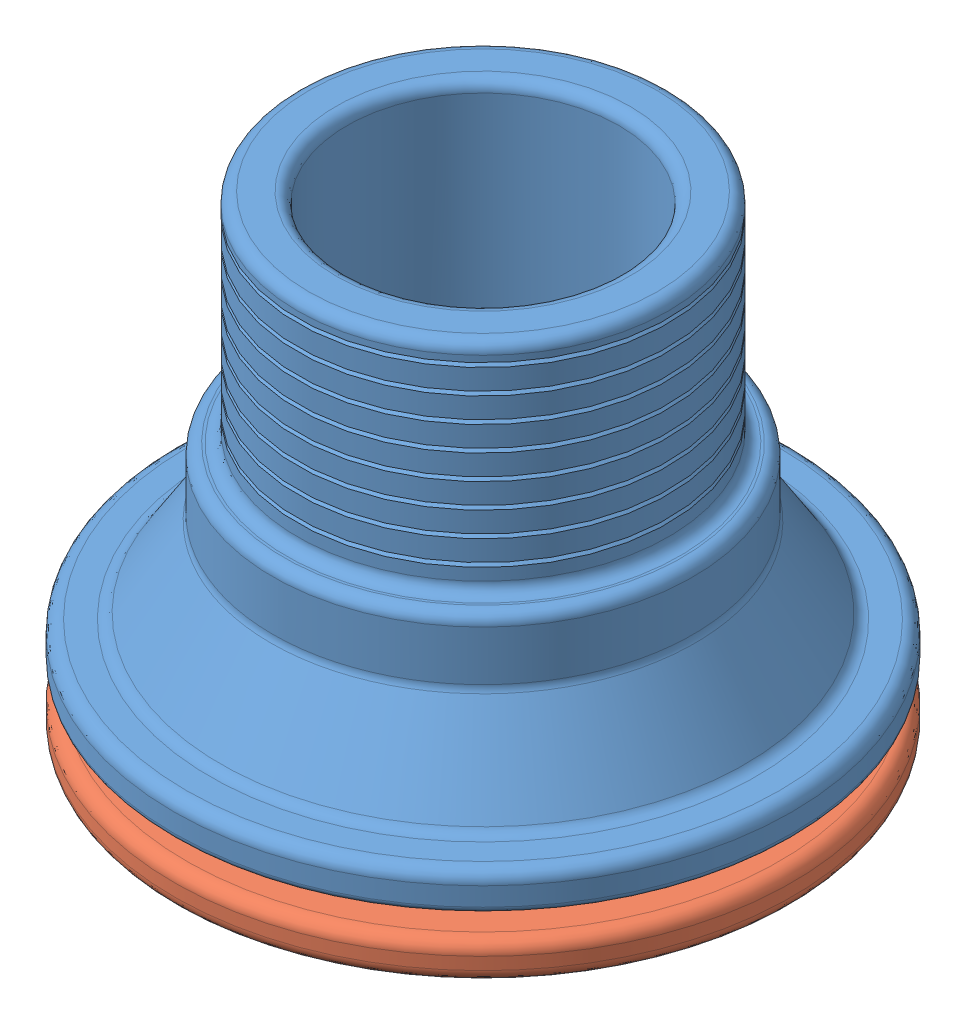
SolidWorks assembly L-TF, configuration Default. Lengths in mm.
Overall size (69.25 37.94 69.25).
3 component instances, 3 part files, 1 mates.
Components (placement in the parent):
- thruHullFitting_female-1: thruHullFitting_female [Default] at (8.5642 7.6881 44.6629) size (50 33 50)
- thruHullFitting_male-1: thruHullFitting_male [Default] at (8.5642 2.7452 44.6629) x (0.835375 0 0.549681) z (-0.549681 0 0.835375) size (50 16 50)
- thruHullFitting_oring-1: thruHullFitting_oring [Default] at (8.8398 17.842 45.2702) x (0 1 0) z (0 0 1) size (2 26 26)
Mates (geometry in assembly coordinates):
- Concentric1: concentric: cylinder of thruHullFitting_female-1 through (8.5642 7.6881 44.6629) axis (0 -1 0) radius 25; cylinder of thruHullFitting_male-1 through (8.5642 5.7452 44.6629) axis (0 -1 0) radius 25
